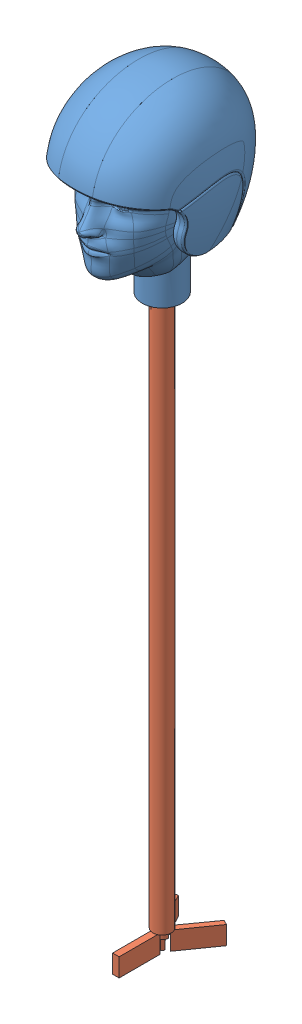
SolidWorks assembly Assem1, configuration Default. Lengths in mm.
Overall size (232.75 1253.76 255.82).
2 component instances, 2 part files, 5 mates.
Components (placement in the parent):
- Helmet-1: Helmet [Default] at (28.1197 -1643.9379 -10.335) size (232.75 323.76 255.82)
- stand maniquin-1: stand maniquin [Default] at (28.1197 -180.1279 -20.5487) x (1 0 0) z (0 -1 0) size (90.52 137.38 930)
Mates (geometry in assembly coordinates):
- Coincident1: coincident: plane of Helmet-1 through (28.1197 -180.1279 -20.5487) normal (0 -1 0); plane of stand maniquin-1 through (116.0465 -180.1279 -196.7499) normal (0 1 0)
- Coincident3: coincident: plane of Helmet-1 through (28.1197 -180.1279 -20.5487) normal (0 -1 0); plane of stand maniquin-1 through (116.0465 -180.1279 -196.7499) normal (0 1 0)
- Parallel1: parallel: plane of Helmet-1 through (28.1197 -180.1279 -20.5487) normal (0 -1 0); plane of stand maniquin-1 through (116.0465 -1110.1279 -196.7499) normal (0 -1 0)
- Tangent3: tangent: plane of Helmet-1 through (28.1197 -180.1279 -20.5487) normal (0 -1 0); circle of stand maniquin-1
- Concentric1: concentric anti-aligned: circle of Helmet-1; circle of stand maniquin-1
